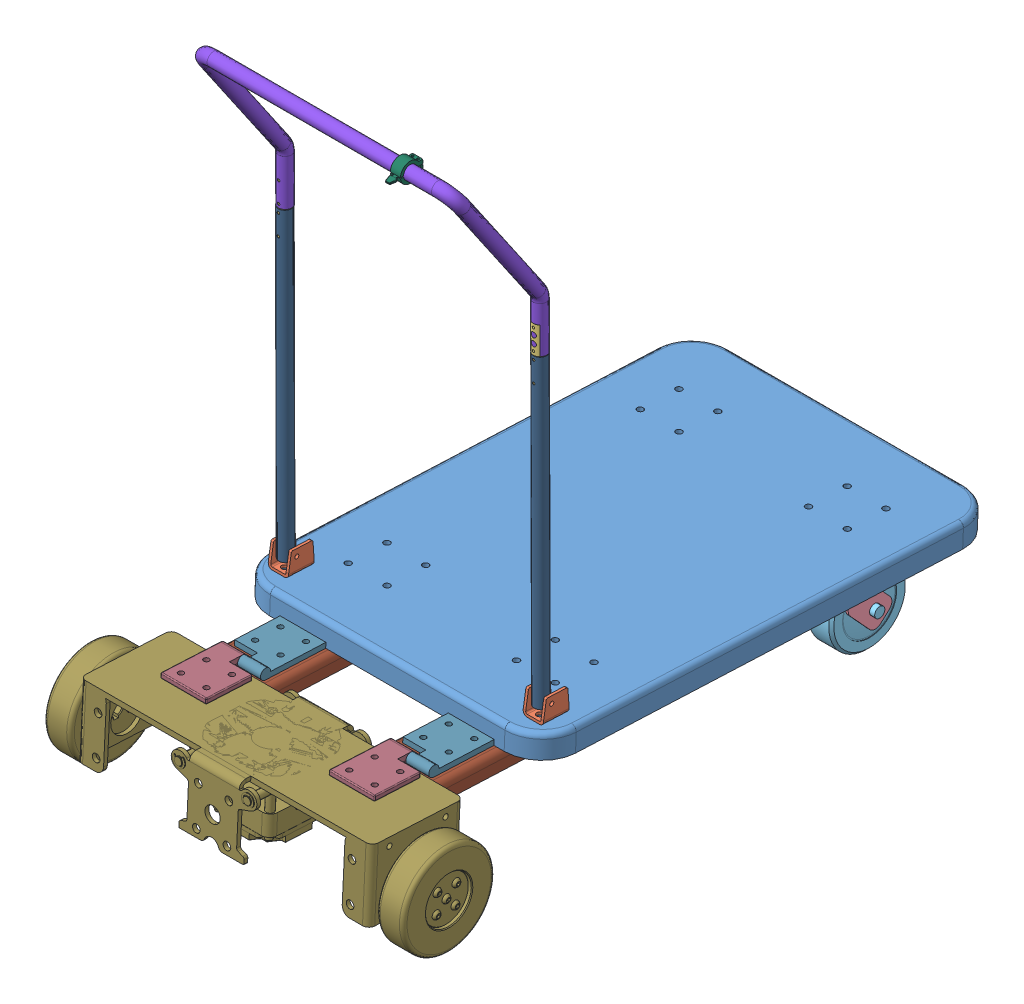
SolidWorks assembly PlanA, configuration 默认. Lengths in mm.
Overall size (705 1259.56 1251.77).
35 component instances, 16 part files, 71 mates.
Components (placement in the parent):
- panel^PlanA-1: panel^PlanA [默认] at (0 -24.9201 0.9855) x (1 0 0) z (0 0.043859 0.999038) size (600 45 900) (virtual)
- Hinge^PlanA-1: Hinge^PlanA [默认] at (-250 43.2316 413.3565) x (1 0 0) z (0 0.043859 0.999038) size (40 45 50) (virtual)
- Hinge^PlanA-2: Hinge^PlanA [默认] at (250 43.2316 413.3565) x (1 0 0) z (0 0.043859 0.999038) size (40 45 50) (virtual)
- con1^PlanA-1: con1^PlanA [默认] at (248 684.0074 398.8374) x (0 -0.002646 0.999997) z (0 -0.999997 -0.002646) size (25 18 54) (virtual)
- con1^PlanA-2: con1^PlanA [默认] at (-252 629.0076 398.6919) x (0 0.002646 -0.999997) z (0 0.999997 0.002646) size (25 18 54) (virtual)
- Wheelasssembly-4: Wheelasssembly [Default] at (202.9636 -19.1981 -401.2915) x (-1 0 0) z (0 0.043859 0.999038) size (100 193.9 158.85)
  - 1TrolleyWheelSupport-1: 1TrolleyWheelSupport [Default] at (37.9636 23.3598 114.9093) size (100 152.99 117.95)
  - 1TrolleyWheel-1: 1TrolleyWheel [Default] at (37.9636 142.258 89.0548) size (90 150 150)
- Wheelasssembly-5: Wheelasssembly [Default] at (-127.0364 -19.1981 -401.2915) x (-1 0 0) z (0 0.043859 0.999038) size (100 193.9 158.85)
  - 1TrolleyWheelSupport-1: 1TrolleyWheelSupport [Default] at (37.9636 23.3598 114.9093) size (100 152.99 117.95)
  - 1TrolleyWheel-1: 1TrolleyWheel [Default] at (37.9636 142.258 89.0548) size (90 150 150)
- handle^PlanA-1: handle^PlanA [默认] at (248 656.5085 398.4146) x (0 -0.002646 0.999997) z (0 -0.999997 -0.002646) size (12.7 12.7 80) (virtual)
- handle^PlanA-2: handle^PlanA [默认] at (-252 656.5085 398.4146) x (0 -0.002646 0.999997) z (0 0.999997 0.002646) size (12.7 12.7 80) (virtual)
- 5垫片^PlanA-1: 5垫片^PlanA [默认] at (-252 636.4917 404.7117) x (-0.0003 0.999996 0.002646) z (0 -0.002646 0.999997) size (10 10 1) (virtual)
- 5垫片^PlanA-2: 5垫片^PlanA [默认] at (-252 621.4918 404.672) x (-0.0003 0.999996 0.002646) z (0 -0.002646 0.999997) size (10 10 1) (virtual)
- 5垫片^PlanA-3: 5垫片^PlanA [默认] at (248 676.4916 404.8175) x (-0.0003 0.999996 0.002646) z (0 -0.002646 0.999997) size (10 10 1) (virtual)
- 5垫片^PlanA-4: 5垫片^PlanA [默认] at (248 691.4915 404.8572) x (-0.0003 0.999996 0.002646) z (0 -0.002646 0.999997) size (10 10 1) (virtual)
- 零件2^PlanA-1: 零件2^PlanA [默认] at (-2 1003.8166 568.1497) x (1 0 0) z (0 -0.002646 0.999997) size (526 360.26 195.17) (virtual)
- 4垫片^PlanA-1: 4垫片^PlanA [默认] at (-252 676.5278 391.1176) x (-0.0003 0.999996 0.002646) z (0 -0.002646 0.999997) size (10 10 1) (virtual)
- 4垫片^PlanA-3: 4垫片^PlanA [默认] at (-252 691.5278 391.1573) x (-0.158849 0.987299 0.002612) z (0 -0.002646 0.999997) size (10 10 1) (virtual)
- 4垫片^PlanA-5: 4垫片^PlanA [默认] at (248 621.528 390.9721) x (-0.378264 0.925694 0.002449) z (0 -0.002646 0.999997) size (10 10 1) (virtual)
- 4垫片^PlanA-7: 4垫片^PlanA [默认] at (248 636.528 391.0118) x (-0.516203 0.856463 0.002266) z (0 -0.002646 0.999997) size (10 10 1) (virtual)
- con1^PlanA-3: con1^PlanA [默认] at (248 629.0095 397.9919) x (0 -0.002646 0.999997) z (0 -0.999997 -0.002646) size (25 18 54) (virtual)
- con1^PlanA-4: con1^PlanA [默认] at (-252 684.0093 398.1374) x (0 -0.002646 0.999997) z (0 -0.999997 -0.002646) size (25 18 54) (virtual)
- 零件4^PlanA-1: 零件4^PlanA [默认] at (248 56.5115 396.4773) x (-1 0 0) z (0 0.002646 -0.999997) size (26 599.5 26) (virtual)
- 零件4^PlanA-2: 零件4^PlanA [默认] at (-252 56.5096 397.1773) x (-1 0 0) z (0 0.002646 -0.999997) size (26 599.5 26) (virtual)
- A^PlanA-1: A^PlanA [默认] at (-165 -17.8077 231.3971) x (1 0 0) z (0 0.043859 0.999038) size (126 33 500) (virtual)
- A^PlanA-2: A^PlanA [默认] at (165 -17.8077 231.3971) x (1 0 0) z (0 0.043859 0.999038) size (126 33 500) (virtual)
- 平衡车-1: 平衡车 [默认] at (0 15.3984 676.0987) x (1 0 0) z (0 0.050067 0.998746) size (705 187.5 231.75)
- 零件3^PlanA-2: 零件3^PlanA [默认] at (-165 23.5726 639.4263) x (-1 0 0) z (0 0.050067 0.998746) size (90 20 126.61) (virtual)
- 零件3^PlanA-3: 零件3^PlanA [默认] at (165 23.5726 639.4263) x (-1 0 0) z (0 0.050067 0.998746) size (90 20 126.61) (virtual)
- 零件7^PlanA-1: 零件7^PlanA [默认] at (165 6.7407 494.1665) x (1 0 0) z (0 -0.043859 -0.999038) size (90 20 129.31) (virtual)
- 零件7^PlanA-2: 零件7^PlanA [默认] at (-165 6.7407 494.1665) x (1 0 0) z (0 -0.043859 -0.999038) size (90 20 129.31) (virtual)
- 零件1^PlanA-1: 零件1^PlanA [默认] at (143.3016 1003.8166 568.1497) x (1 0 0) z (0 -0.045311 0.998973) size (20 38 60.16) (virtual)
- 零件5^PlanA-1: 零件5^PlanA [默认] at origin (virtual)
Mates (geometry in assembly coordinates):
- 重合1: coincident anti-aligned: plane of panel^不延伸的-1 through (230 36.703 378.6462) normal (0 0.999038 -0.043859); plane of Hinge^不延伸的-1 through (-235 38.2364 413.5757) normal (0 -0.999038 0.043859)
- 同心1: concentric aligned: cylinder of panel^不延伸的-1 through (-250 37.6882 401.0878) axis (0 0.999038 -0.043859) radius 6; cylinder of Hinge^不延伸的-1 through (-250 42.6834 400.8685) axis (0 0.999038 -0.043859) radius 6
- 同心2: concentric aligned: cylinder of panel^不延伸的-1 through (-250 36.5917 376.1118) axis (0 0.999038 -0.043859) radius 6; cylinder of Hinge^不延伸的-1 through (-250 41.5869 375.8925) axis (0 0.999038 -0.043859) radius 6
- 重合2: coincident anti-aligned: plane of panel^不延伸的-1 through (230 36.703 378.6462) normal (0 0.999038 -0.043859); plane of Hinge^不延伸的-2 through (265 38.2364 413.5757) normal (0 -0.999038 0.043859)
- 同心3: concentric aligned: cylinder of panel^不延伸的-1 through (250 37.6882 401.0878) axis (0 0.999038 -0.043859) radius 6; cylinder of Hinge^不延伸的-2 through (250 42.6834 400.8685) axis (0 0.999038 -0.043859) radius 6
- 同心4: concentric aligned: cylinder of panel^不延伸的-1 through (250 36.5917 376.1118) axis (0 0.999038 -0.043859) radius 6; cylinder of Hinge^不延伸的-2 through (250 41.5869 375.8925) axis (0 0.999038 -0.043859) radius 6
- 重合9: coincident anti-aligned: plane of panel^不延伸的-1 through (230 -8.2537 380.6199) normal (0 -0.999038 0.043859); plane of Wheelasssembly-4/1TrolleyWheelSupport-1 through (165 -37.4957 -285.4683) normal (0 0.999038 -0.043859)
- 同心18: concentric anti-aligned: cylinder of panel^不延伸的-1 through (127 5.8002 -325.2738) axis (0 0.999038 -0.043859) radius 6; cylinder of Wheelasssembly-4/1TrolleyWheelSupport-1 through (127 -39.1565 -323.3001) axis (0 -0.999038 0.043859) radius 5.5
- 同心19: concentric anti-aligned: cylinder of panel^不延伸的-1 through (203 5.8002 -325.2738) axis (0 0.999038 -0.043859) radius 6; cylinder of Wheelasssembly-4/1TrolleyWheelSupport-1 through (203 -39.1565 -323.3001) axis (0 -0.999038 0.043859) radius 5.5
- 重合10: coincident anti-aligned: plane of panel^不延伸的-1 through (230 -8.2537 380.6199) normal (0 -0.999038 0.043859); plane of Wheelasssembly-5/1TrolleyWheelSupport-1 through (-165 -37.4957 -285.4683) normal (0 0.999038 -0.043859)
- 同心20: concentric anti-aligned: cylinder of panel^不延伸的-1 through (-203 5.8002 -325.2738) axis (0 0.999038 -0.043859) radius 6; cylinder of Wheelasssembly-5/1TrolleyWheelSupport-1 through (-203 -39.1565 -323.3001) axis (0 -0.999038 0.043859) radius 5.5
- 同心21: concentric anti-aligned: cylinder of panel^不延伸的-1 through (-127 5.8002 -325.2738) axis (0 0.999038 -0.043859) radius 6; cylinder of Wheelasssembly-5/1TrolleyWheelSupport-1 through (-127 -39.1565 -323.3001) axis (0 -0.999038 0.043859) radius 5.5
- 同心24: concentric aligned: cylinder of con1^不延伸的-1 through (248 691.4743 411.3572) axis (0 -0.002646 0.999997) radius 2.75; cylinder of handle^不延伸的-1 through (248 691.4915 404.8572) axis (0 -0.002646 0.999997) radius 2.1
- 同心25: concentric aligned: cylinder of con1^不延伸的-1 through (248 676.4744 411.3175) axis (0 -0.002646 0.999997) radius 2.75; cylinder of handle^不延伸的-1 through (248 676.4916 404.8175) axis (0 -0.002646 0.999997) radius 2.1
- 同心26: concentric anti-aligned: cylinder of con1^不延伸的-2 through (-252 636.5407 386.2118) axis (0 0.002646 -0.999997) radius 2.75; cylinder of handle^不延伸的-2 through (-252 636.4917 404.7117) axis (0 -0.002646 0.999997) radius 2.1
- 同心27: concentric anti-aligned: cylinder of con1^不延伸的-2 through (-252 621.5407 386.1721) axis (0 0.002646 -0.999997) radius 2.75; cylinder of handle^不延伸的-2 through (-252 621.4918 404.672) axis (0 -0.002646 0.999997) radius 2.1
- 重合13: coincident anti-aligned: plane of con1^不延伸的-2 through (-252 601.4892 405.6191) normal (0 0.002646 -0.999997); plane of 5垫片^不延伸的-1 through (-252 636.4891 405.7117) normal (0 -0.002646 0.999997)
- 同心28: concentric aligned: cylinder of con1^不延伸的-2 through (-252 636.5407 386.2118) axis (0 0.002646 -0.999997) radius 2.75; cylinder of 5垫片^不延伸的-1 through (-252 636.4891 405.7117) axis (0 0.002646 -0.999997) radius 2.6
- 同心29: concentric aligned: cylinder of con1^不延伸的-2 through (-252 621.5407 386.1721) axis (0 0.002646 -0.999997) radius 2.75; cylinder of 5垫片^不延伸的-2 through (-252 621.4891 405.672) axis (0 0.002646 -0.999997) radius 2.6
- 重合14: coincident anti-aligned: plane of con1^不延伸的-2 through (-252 601.4892 405.6191) normal (0 0.002646 -0.999997); plane of 5垫片^不延伸的-2 through (-252 621.4891 405.672) normal (0 -0.002646 0.999997)
- 重合16: coincident anti-aligned: plane of con1^不延伸的-1 through (248 711.4888 405.9101) normal (0 0.002646 -0.999997); plane of 5垫片^不延伸的-3 through (248 676.489 405.8175) normal (0 -0.002646 0.999997)
- 重合17: coincident anti-aligned: plane of con1^不延伸的-1 through (248 711.4888 405.9101) normal (0 0.002646 -0.999997); plane of 5垫片^不延伸的-4 through (248 691.4889 405.8572) normal (0 -0.002646 0.999997)
- 同心30: concentric anti-aligned: cylinder of con1^不延伸的-1 through (248 691.4743 411.3572) axis (0 -0.002646 0.999997) radius 2.75; cylinder of 5垫片^不延伸的-4 through (248 691.4889 405.8572) axis (0 0.002646 -0.999997) radius 2.6
- 同心31: concentric anti-aligned: cylinder of con1^不延伸的-1 through (248 676.4744 411.3175) axis (0 -0.002646 0.999997) radius 2.75; cylinder of 5垫片^不延伸的-3 through (248 676.489 405.8175) axis (0 0.002646 -0.999997) radius 2.6
- 重合18: coincident anti-aligned: plane of handle^不延伸的-1 through (241.65 616.4918 404.6588) normal (0 -0.002646 0.999997); plane of 5垫片^不延伸的-3 through (248 676.4916 404.8175) normal (0 0.002646 -0.999997)
- 重合19: coincident anti-aligned: plane of handle^不延伸的-2 through (-245.65 696.4915 404.8704) normal (0 -0.002646 0.999997); plane of 5垫片^不延伸的-1 through (-252 636.4917 404.7117) normal (0 0.002646 -0.999997)
- 重合21: coincident anti-aligned: plane of handle^不延伸的-2 through (-245.65 696.5251 392.1705) normal (0 0.002646 -0.999997); plane of 4垫片^不延伸的-1 through (-252 676.5252 392.1176) normal (0 -0.002646 0.999997)
- 同心33: concentric anti-aligned: cylinder of handle^不延伸的-2 through (-252 676.4916 404.8175) axis (0 -0.002646 0.999997) radius 1.65; cylinder of 4垫片^不延伸的-1 through (-252 676.5252 392.1176) axis (0 0.002646 -0.999997) radius 2.25
- 重合23: coincident anti-aligned: plane of handle^不延伸的-2 through (-245.65 696.5251 392.1705) normal (0 0.002646 -0.999997); plane of 4垫片^不延伸的-3 through (-252 691.5251 392.1573) normal (0 -0.002646 0.999997)
- 同心34: concentric anti-aligned: cylinder of handle^不延伸的-2 through (-252 691.4915 404.8572) axis (0 -0.002646 0.999997) radius 1.65; cylinder of 4垫片^不延伸的-3 through (-252 691.5251 392.1573) axis (0 0.002646 -0.999997) radius 2.25
- 重合24: coincident anti-aligned: plane of handle^不延伸的-1 through (241.65 616.5254 391.9588) normal (0 0.002646 -0.999997); plane of 4垫片^不延伸的-5 through (248 621.5254 391.9721) normal (0 -0.002646 0.999997)
- 同心35: concentric anti-aligned: cylinder of handle^不延伸的-1 through (248 621.4918 404.672) axis (0 -0.002646 0.999997) radius 1.65; cylinder of 4垫片^不延伸的-5 through (248 621.5254 391.9721) axis (0 0.002646 -0.999997) radius 2.25
- 重合25: coincident anti-aligned: plane of handle^不延伸的-1 through (241.65 616.5254 391.9588) normal (0 0.002646 -0.999997); plane of 4垫片^不延伸的-7 through (248 636.5253 392.0118) normal (0 -0.002646 0.999997)
- 同心36: concentric anti-aligned: cylinder of handle^不延伸的-1 through (248 636.4917 404.7117) axis (0 -0.002646 0.999997) radius 1.65; cylinder of 4垫片^不延伸的-7 through (248 636.5253 392.0118) axis (0 0.002646 -0.999997) radius 2.25
- 重合26: coincident anti-aligned: plane of 4垫片^不延伸的-7 through (248 636.528 391.0118) normal (0 0.002646 -0.999997); plane of con1^不延伸的-3 through (248 656.5279 391.0647) normal (0 -0.002646 0.999997)
- 同心37: concentric anti-aligned: cylinder of handle^不延伸的-1 through (248 621.4918 404.672) axis (0 -0.002646 0.999997) radius 1.65; cylinder of con1^不延伸的-3 through (248 621.5426 385.4721) axis (0 0.002646 -0.999997) radius 2.25
- 同心38: concentric anti-aligned: cylinder of handle^不延伸的-1 through (248 636.4917 404.7117) axis (0 -0.002646 0.999997) radius 1.65; cylinder of con1^不延伸的-3 through (248 636.5425 385.5118) axis (0 0.002646 -0.999997) radius 2.25
- 重合27: coincident anti-aligned: plane of 4垫片^不延伸的-1 through (-252 676.5278 391.1176) normal (0 0.002646 -0.999997); plane of con1^不延伸的-4 through (-252 711.5277 391.2102) normal (0 -0.002646 0.999997)
- 同心39: concentric anti-aligned: cylinder of handle^不延伸的-2 through (-252 676.4916 404.8175) axis (0 -0.002646 0.999997) radius 1.65; cylinder of con1^不延伸的-4 through (-252 676.5424 385.6176) axis (0 0.002646 -0.999997) radius 2.25
- 同心40: concentric anti-aligned: cylinder of handle^不延伸的-2 through (-252 691.4915 404.8572) axis (0 -0.002646 0.999997) radius 1.65; cylinder of con1^不延伸的-4 through (-252 691.5423 385.6573) axis (0 0.002646 -0.999997) radius 2.25
- 同心41: concentric anti-aligned: cylinder of 零件2^不延伸的-1 through (248 747.2441 398.3047) axis (0 -0.999997 -0.002646) radius 12.5; cylinder of con1^不延伸的-3 through (248 601.5096 397.9191) axis (0 0.999997 0.002646) radius 12.5
- 同心42: concentric anti-aligned: cylinder of 零件2^不延伸的-1 through (-252 747.2441 398.3047) axis (0 -0.999997 -0.002646) radius 12.5; cylinder of con1^不延伸的-4 through (-252 656.5094 398.0646) axis (0 0.999997 0.002646) radius 12.5
- 同心44: concentric aligned: cylinder of con1^不延伸的-1 through (248 703.9743 411.3903) axis (0 -0.002646 0.999997) radius 2.1; cylinder of 零件2^不延伸的-1 through (248 704.0436 385.1904) axis (0 -0.002646 0.999997) radius 2.5
- 同心45: concentric aligned: cylinder of 零件2^不延伸的-1 through (-252 704.0436 385.1904) axis (0 -0.002646 0.999997) radius 2.5; cylinder of con1^不延伸的-4 through (-252 703.9762 410.6903) axis (0 -0.002646 0.999997) radius 2.1
- 同心46: concentric anti-aligned: cylinder of con1^不延伸的-3 through (248 601.5096 397.9191) axis (0 0.999997 0.002646) radius 12.5; cylinder of 零件4^不延伸的-1 through (248 656.5094 398.0646) axis (0 -0.999997 -0.002646) radius 12.5
- 同心47: concentric anti-aligned: cylinder of con1^不延伸的-3 through (248 648.9763 410.5448) axis (0 -0.002646 0.999997) radius 2.1; cylinder of 零件4^不延伸的-1 through (248 648.975 411.0448) axis (0 0.002646 -0.999997) radius 2.5
- 同心48: concentric aligned: cylinder of con1^不延伸的-2 through (-252 656.5075 398.7646) axis (0 -0.999997 -0.002646) radius 12.5; cylinder of 零件4^不延伸的-2 through (-252 656.5075 398.7646) axis (0 -0.999997 -0.002646) radius 12.5
- 同心49: concentric aligned: cylinder of con1^不延伸的-2 through (-252 649.0406 386.2448) axis (0 0.002646 -0.999997) radius 2.1; cylinder of 零件4^不延伸的-2 through (-252 648.9732 411.7448) axis (0 0.002646 -0.999997) radius 2.5
- 同心50: concentric anti-aligned: cylinder of Hinge^不延伸的-1 through (-235 69.0096 397.2103) axis (1 0 0) radius 4; cylinder of 零件4^不延伸的-2 through (-239 69.0096 397.2103) axis (-1 0 0) radius 6
- 相切3: tangent anti-aligned: plane of Hinge^不延伸的-1 through (-265 43.2316 413.3565) normal (1 0 0); cylinder of 零件4^不延伸的-2 through (-252 656.5075 398.7646) axis (0 -0.999997 -0.002646) radius 13
- 重合28: coincident anti-aligned: plane of panel^不延伸的-1 through (230 -8.2537 380.6199) normal (0 -0.999038 0.043859); plane of A^不延伸的-1 through (-215 7.1188 730.7844) normal (0 0.999038 -0.043859)
- 同心51: concentric aligned: cylinder of panel^不延伸的-1 through (-203 34.2731 323.2976) axis (0 0.999038 -0.043859) radius 6; cylinder of A^不延伸的-1 through (-203 -10.6836 325.2712) axis (0 0.999038 -0.043859) radius 5.25
- 同心52: concentric aligned: cylinder of panel^不延伸的-1 through (-127 30.9398 247.3707) axis (0 0.999038 -0.043859) radius 6; cylinder of A^不延伸的-1 through (-127 -14.0169 249.3443) axis (0 0.999038 -0.043859) radius 5.25
- 重合29: coincident anti-aligned: plane of panel^不延伸的-1 through (230 -8.2537 380.6199) normal (0 -0.999038 0.043859); plane of A^不延伸的-2 through (115 7.1188 730.7844) normal (0 0.999038 -0.043859)
- 同心53: concentric aligned: cylinder of panel^不延伸的-1 through (127 34.2731 323.2976) axis (0 0.999038 -0.043859) radius 6; cylinder of A^不延伸的-2 through (127 -10.6836 325.2712) axis (0 0.999038 -0.043859) radius 5.25
- 同心54: concentric aligned: cylinder of panel^不延伸的-1 through (203 30.9398 247.3707) axis (0 0.999038 -0.043859) radius 6; cylinder of A^不延伸的-2 through (203 -14.0169 249.3443) axis (0 0.999038 -0.043859) radius 5.25
- 重合32: coincident anti-aligned: plane of 平衡车-1 through (274.5 11.4933 598.1966) normal (0 0.998746 -0.050067); plane of 零件3^不延伸的-3 through (165 13.5852 639.927) normal (0 -0.998746 0.050067)
- 同心57: concentric anti-aligned: cylinder of 平衡车-1 through (190 14.8368 664.8956) axis (0 0.998746 -0.050067) radius 5.25; cylinder of 零件3^不延伸的-3 through (190 14.8368 664.8956) axis (0 -0.998746 0.050067) radius 5.25
- 同心58: concentric anti-aligned: cylinder of 平衡车-1 through (140 12.3335 614.9583) axis (0 0.998746 -0.050067) radius 5.25; cylinder of 零件3^不延伸的-3 through (140 12.3335 614.9583) axis (0 -0.998746 0.050067) radius 5.25
- 重合33: coincident anti-aligned: plane of 平衡车-1 through (274.5 11.4933 598.1966) normal (0 0.998746 -0.050067); plane of 零件3^不延伸的-2 through (-165 13.5852 639.927) normal (0 -0.998746 0.050067)
- 同心59: concentric anti-aligned: cylinder of 平衡车-1 through (-140 12.3335 614.9583) axis (0 0.998746 -0.050067) radius 5.25; cylinder of 零件3^不延伸的-2 through (-140 12.3335 614.9583) axis (0 -0.998746 0.050067) radius 5.25
- 同心60: concentric anti-aligned: cylinder of 平衡车-1 through (-190 14.8368 664.8956) axis (0 0.998746 -0.050067) radius 5.25; cylinder of 零件3^不延伸的-2 through (-190 14.8368 664.8956) axis (0 -0.998746 0.050067) radius 5.25
- 重合34: coincident anti-aligned: plane of 零件3^不延伸的-3 through (165 23.5726 639.4263) normal (1 0 0); plane of 零件7^不延伸的-1 through (165 6.7407 494.1665) normal (-1 0 0)
- 同心61: concentric anti-aligned: cylinder of 零件3^不延伸的-3 through (78.2847 10 568.4085) axis (1 0 0) radius 10; cylinder of 零件7^不延伸的-1 through (254.1084 10 568.4085) axis (-1 0 0) radius 10
- 重合35: coincident anti-aligned: plane of 零件3^不延伸的-2 through (-165 23.5726 639.4263) normal (1 0 0); plane of 零件7^不延伸的-2 through (-165 6.7407 494.1665) normal (-1 0 0)
- 同心62: concentric anti-aligned: cylinder of 零件3^不延伸的-2 through (-251.7153 10 568.4085) axis (1 0 0) radius 10; cylinder of 零件7^不延伸的-2 through (-75.8916 10 568.4085) axis (-1 0 0) radius 10
- 重合38: coincident anti-aligned: plane of A^不延伸的-2 through (115 7.1188 730.7844) normal (0 0.999038 -0.043859); plane of 零件7^不延伸的-1 through (165 -3.2497 494.6051) normal (0 -0.999038 0.043859)
- 重合39: coincident anti-aligned: plane of A^不延伸的-1 through (-215 7.1188 730.7844) normal (0 0.999038 -0.043859); plane of 零件7^不延伸的-2 through (-165 -3.2497 494.6051) normal (0 -0.999038 0.043859)
- 同心64: concentric anti-aligned: cylinder of A^不延伸的-2 through (190 -4.3461 469.6292) axis (0 0.999038 -0.043859) radius 5.25; cylinder of 零件7^不延伸的-1 through (190 -4.3461 469.6292) axis (0 -0.999038 0.043859) radius 5.25
- 同心65: concentric anti-aligned: cylinder of A^不延伸的-1 through (-190 -2.1532 519.581) axis (0 0.999038 -0.043859) radius 5.25; cylinder of 零件7^不延伸的-2 through (-190 -2.1532 519.581) axis (0 -0.999038 0.043859) radius 5.25
- 同心66: concentric anti-aligned: cylinder of 零件2^PlanA-1 through (-2 1003.8166 568.1497) axis (1 0 0) radius 13; cylinder of 零件1^PlanA-1 through (163.3016 1003.8166 568.1497) axis (-1 0 0) radius 13
